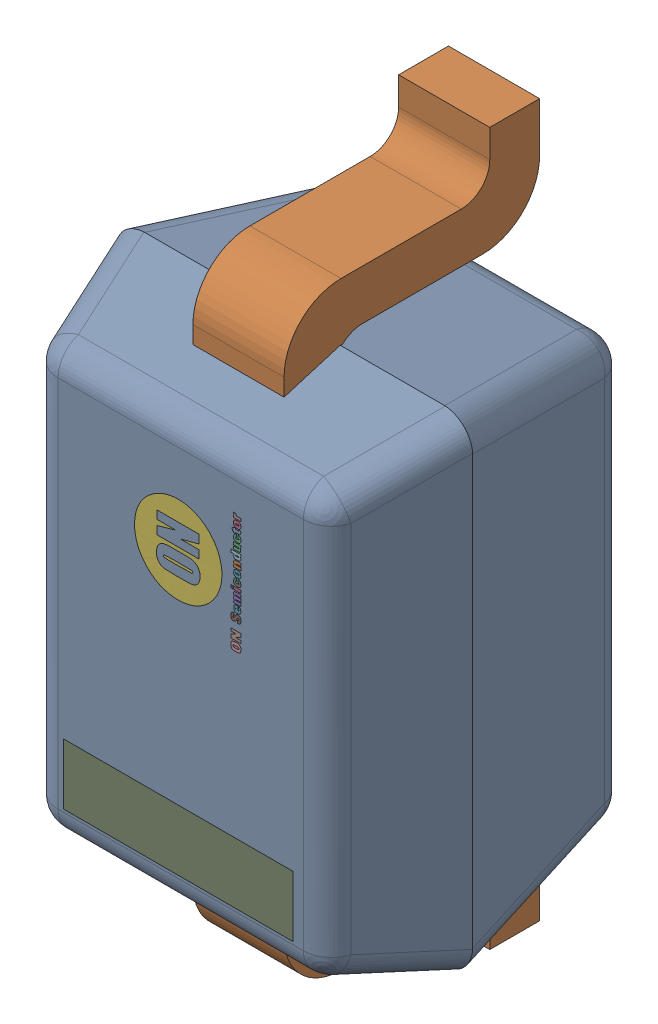
SolidWorks assembly Zener1, configuration Défaut. Lengths in mm.
Overall size (1.25 2.5 1.12).
5 component instances, 4 part files, 0 mates.
Components (placement in the parent):
- Diode_ON_Semiconductor_NSR02100HT1G_eec-1: Diode_ON_Semiconductor_NSR02100HT1G_eec [Défaut] at (-12.827 28.829 0) x (0 1 0) z (0 0 1) size (2.5 1.25 1.12)
  - 1-1: 1 [Défaut] at (0 0 0.05) size (1.7 1.25 1.08)
  - 2-1: 2 [Défaut] x (1 0 0) z (0 -1 0) size (2.5 0.9 0.32)
  - ON Semiconductor-1: ON Semiconductor [Défaut] at (0.2865 -0.4575 1.0977) size (0.43 0.38 0.01)
  - bar-1: bar [Défaut] at (0 0 1.1) size (0.22 0.81 0)
